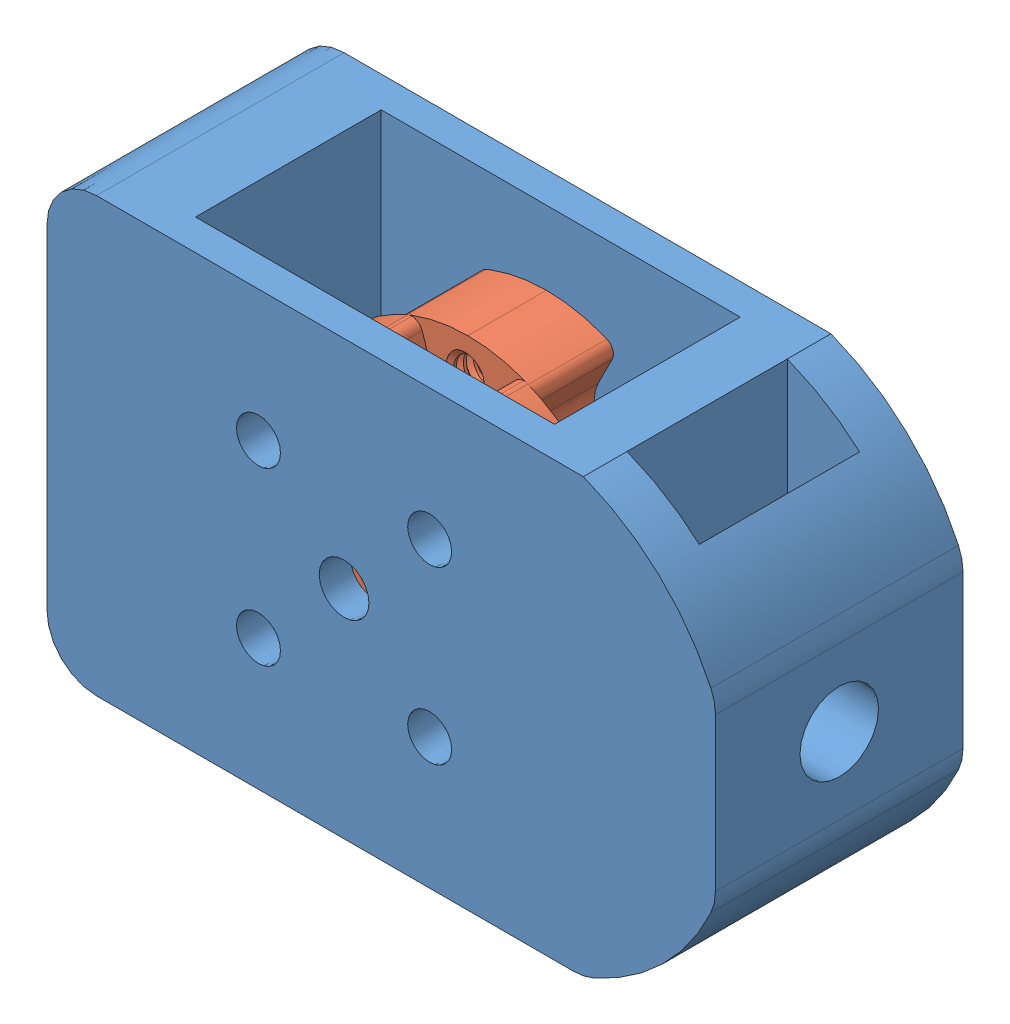
SolidWorks assembly ARMUS-REV2-200, configuration Défaut. Lengths in mm.
Overall size (54 35 20).
3 component instances, 3 part files, 9 mates.
Components (placement in the parent):
- ARMUS-REV2-201-1: ARMUS-REV2-201 [Défaut] at origin size (54 35 20)
- HUB-0_25-1: HUB-0_25 [Défaut] at (-30.0172 37.5992 -6.2696) x (-1 0 0) z (0 -1 0) size (25.4 12.7 25.4)
- hex nut_ai-2: hex nut_ai [HNUT 0.2500-20-D-N] at (19.3798 17.5 0) x (0 0.5 0.866025) z (-1 0 0) size (11.11 12.83 5.74)
Mates (geometry in assembly coordinates):
- Coïncidente1: coordinate: point of ARMUS-REV2-003-1
- Largeur2: width anti-aligned: plane of ARMUS-REV2-003-1 through (14.5 0 7.5) normal (0 0 -1); plane of ARMUS-REV2-003-1 through (14.5 0 -7.5) normal (0 0 1); plane of HUB-0_25-1 through (0 17.5 6.35) normal (0 0 1); plane of HUB-0_25-1 through (0 17.5 -6.35) normal (0 0 -1)
- Largeur3: width aligned: plane of ARMUS-REV2-003-1 through (0 35 0) normal (0 1 0); plane of ARMUS-REV2-003-1 through (0 0 0) normal (0 -1 0); plane of HNUT 0.2500-20-D-N-1 through (25.1202 23.0562 3.2079) normal (0 1 0); plane of HNUT 0.2500-20-D-N-1 through (25.1202 11.9437 -3.2079) normal (0 -1 0)
- Largeur4: width: plane of ARMUS-REV2-003-1 through (30 35 -10) normal (0 0 -1); plane of ARMUS-REV2-003-1 through (30 35 10) normal (0 0 1); cylinder of HNUT 0.2500-20-D-N-1 through (25.1202 17.5 0) axis (-1 0 0) radius 2.5527
- Largeur5: width aligned: plane of ARMUS-REV2-003-1 through (14.5 0 7.5) normal (-1 0 0); plane of ARMUS-REV2-003-1 through (30 35 10) normal (1 0 0); plane of HNUT 0.2500-20-D-N-1 through (19.3798 23.0562 -3.2079) normal (-1 0 0); plane of HNUT 0.2500-20-D-N-1 through (25.1202 23.0562 -3.2079) normal (1 0 0)
- Largeur6: width aligned: plane of ARMUS-REV2-003-1 through (14.5 0 -7.5) normal (0 0 1); plane of HUB-0_25-1 through (14.5 0 7.5) normal (0 0 -1); plane of ARMUS-REV2-003-1 through (0 17.5 6.35) normal (0 0 1); plane of HUB-0_25-1 through (0 17.5 -6.35) normal (0 0 -1)
- Largeur7: width: plane of ARMUS-REV2-003-1 through (14.5 0 7.5) normal (-1 0 0); plane of HUB-0_25-1 through (-14.5 0 7.5) normal (1 0 0); cylinder of ARMUS-REV2-003-1 through (0 17.5 1.5875) axis (0 0 1) radius 3.175
- Parallèle1: parallel anti-aligned: plane of HUB-0_25-1 through (-30.0172 37.5992 -6.2696) normal (-1 0 0)
- Largeur8: width: plane of ARMUS-REV2-003-1 through (0 0 0) normal (0 -1 0); plane of ARMUS-REV2-003-1 through (0 35 0) normal (0 1 0); cylinder of HUB-0_25-1 through (0 17.5 1.5875) axis (0 0 1) radius 3.175
